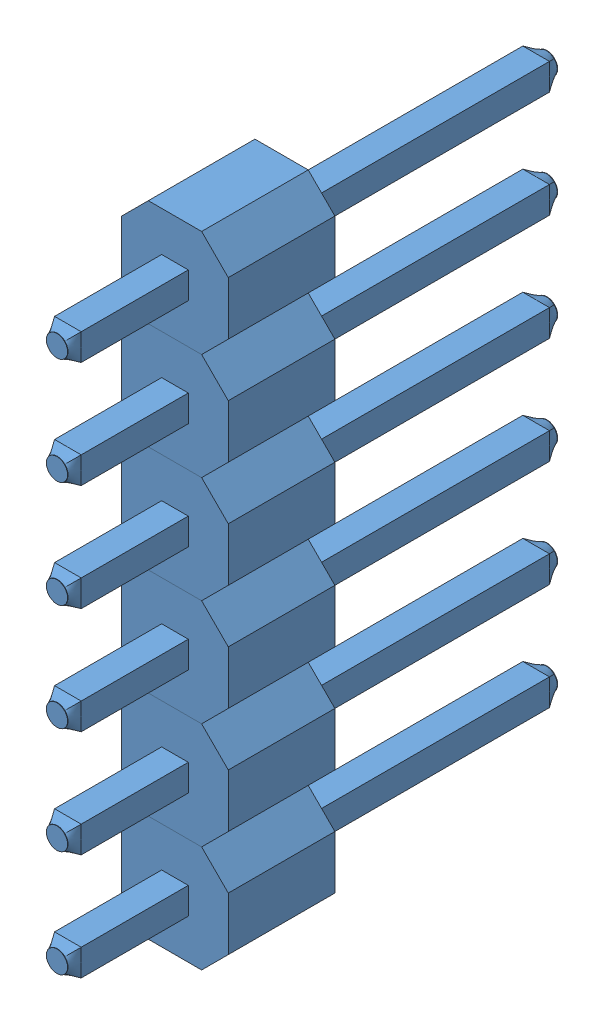
SolidWorks assembly Assem3, configuration Default. Lengths in mm.
Overall size (2.54 15.24 11.76).
6 component instances, 1 part files, 0 mates.
Components (placement in the parent):
- Male Header Pin-1: Male Header Pin [Default] at (-51.078 6.4242 23.0751) size (2.54 2.54 11.76)
- Male Header Pin-2: Male Header Pin [Default] at (-51.078 8.9642 23.0751) size (2.54 2.54 11.76)
- Male Header Pin-3: Male Header Pin [Default] at (-51.078 11.5042 23.0751) size (2.54 2.54 11.76)
- Male Header Pin-4: Male Header Pin [Default] at (-51.078 14.0442 23.0751) size (2.54 2.54 11.76)
- Male Header Pin-5: Male Header Pin [Default] at (-51.078 16.5842 23.0751) size (2.54 2.54 11.76)
- Male Header Pin-6: Male Header Pin [Default] at (-51.078 19.1242 23.0751) size (2.54 2.54 11.76)
